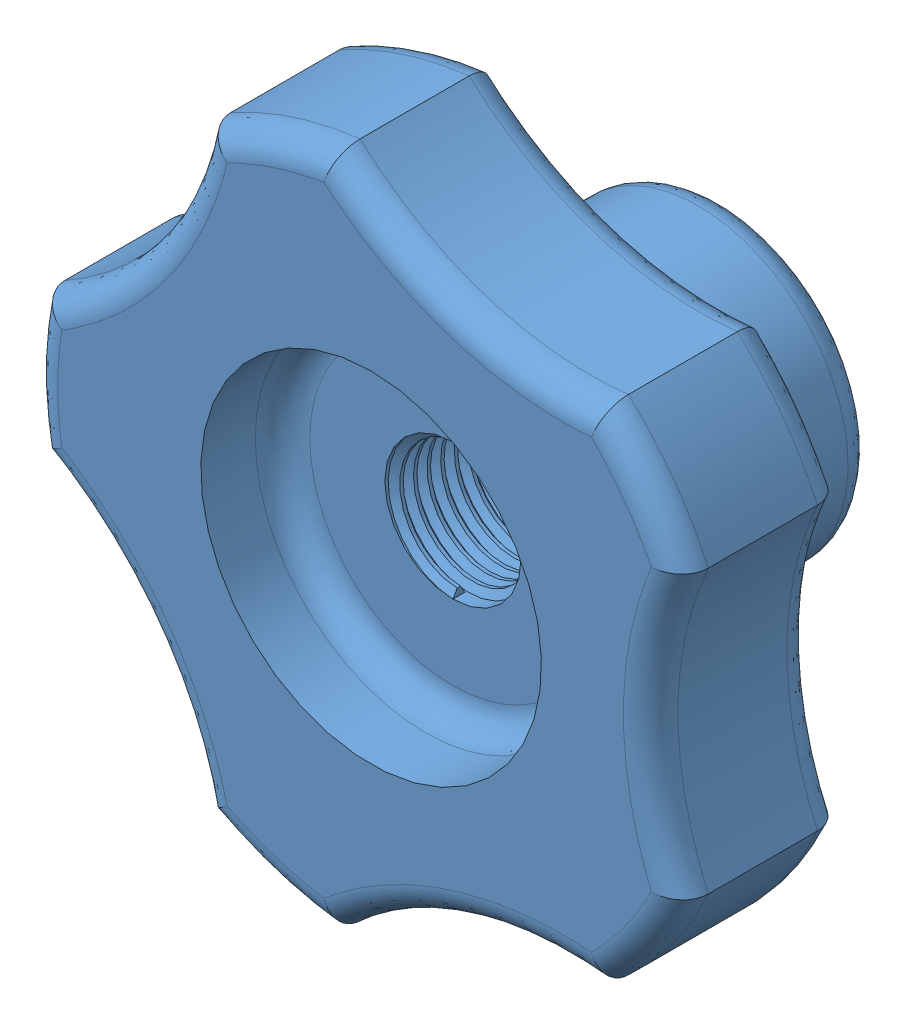
SolidWorks assembly 单螺旋夹紧_星形把手, configuration 默认. Lengths in mm.
Overall size (47.87 49.9 63.11).
3 component instances, 3 part files, 4 mates.
Components (placement in the parent):
- BM10星形把手-1: BM10星形把手 [默认] at (28.2083 4.1039 52.3999) x (0 1 0) z (0 0 1) size (49.9 47.87 26.11)
- AM10×60压紧螺钉-1: AM10×60压紧螺钉 [默认] at (28.2083 4.1039 49.3999) size (10.14 11.55 59.97)
- parallel pins hardening steel gb-2: parallel pins hardening steel gb [GB_CONNECTING_PIECE_PIN_DP 3X22] at (17.2083 4.1039 33.3999) x (1 0 0) z (0 0.764188 0.644994) size (22 3 3)
Mates (geometry in assembly coordinates):
- 同心1: concentric: cylinder of assembly; cylinder of assembly; cylinder of BM10星形把手-1 through (28.2083 4.1039 52.3999) axis (0 0 1) radius 11; cylinder of AM10×60压紧螺钉-1 through (28.2083 4.1039 49.3999) axis (0 0 1) radius 3.5
- 同心2: concentric: cylinder of assembly; cylinder of assembly; cylinder of BM10星形把手-1 through (50.964 4.1039 33.3999) axis (-1 0 0) radius 1.5; cylinder of AM10×60压紧螺钉-1 through (23.2083 4.1039 33.3999) axis (1 0 0) radius 1.5
- 同心3: concentric: cylinder of assembly; cylinder of assembly; cylinder of BM10星形把手-1 through (50.964 4.1039 33.3999) axis (-1 0 0) radius 1.5; cylinder of parallel pins hardening steel gb-2 through (10.2316 4.1039 33.3999) axis (-1 0 0) radius 1.5
- 相切1: tangent: cylinder of assembly; plane of assembly; cylinder of BM10星形把手-1 through (28.2083 4.1039 52.3999) axis (0 0 1) radius 11; plane of parallel pins hardening steel gb-2 through (17.2083 4.985 32.356) normal (-1 0 0)
